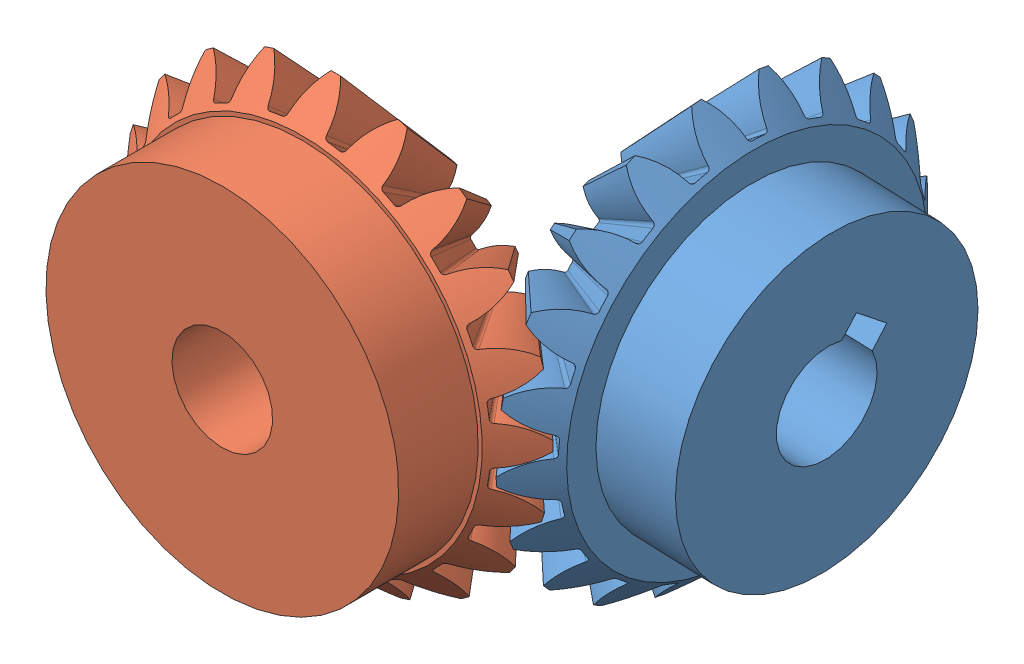
SolidWorks assembly Pinion Gear System, configuration Default. Lengths in mm.
Overall size (55.67 60.71 59.99).
2 component instances, 2 part files, 4 mates.
Components (placement in the parent):
- straight bevel gear_am-1: straight bevel gear_am [Metric - Straight bevel gear 2M 20GT 20PT 20PA 12FW ---20O30H30MD10S1] at (-367.4444 -1387.6419 -30.0001) x (-0.999245 0.038861 0) z (-0.024303 -0.624899 -0.780327) size (19.85 42.67 42.67)
- straight bevel pinion_am-1: straight bevel pinion_am [Metric - Straight bevel pinion 2M20PT 20GT 20PA 12FW ---20O35H30MD10N] at (-389.5287 -1386.783 -7.8991) x (0 0 -1) z (0.986616 0.163058 0) size (19.85 42.67 42.67)
Mates (geometry in assembly coordinates):
- Coincident2: coincident: point of straight bevel gear_am-1; point of straight bevel pinion_am-1
- Perpendicular1: perpendicular: line of straight bevel gear_am-1 through (-357.4519 -1388.0305 -30.0001) axis (-0.999245 0.038861 0); line of straight bevel pinion_am-1 through (-389.5287 -1386.783 2.1009) axis (0 0 -1)
- Coincident4: coincident aligned: plane of straight bevel pinion_am-1 through (-389.5287 -1386.783 0) normal (0 0 1)
- GearMate1: gear = 25.4 : 25.4 mm: cone of straight bevel gear_am-1 through (-370.9569 -1387.5053 -30.0001) axis (0.999245 -0.038861 0); cone of straight bevel pinion_am-1 through (-389.5287 -1386.783 -11.4143) axis (0 0 1)
